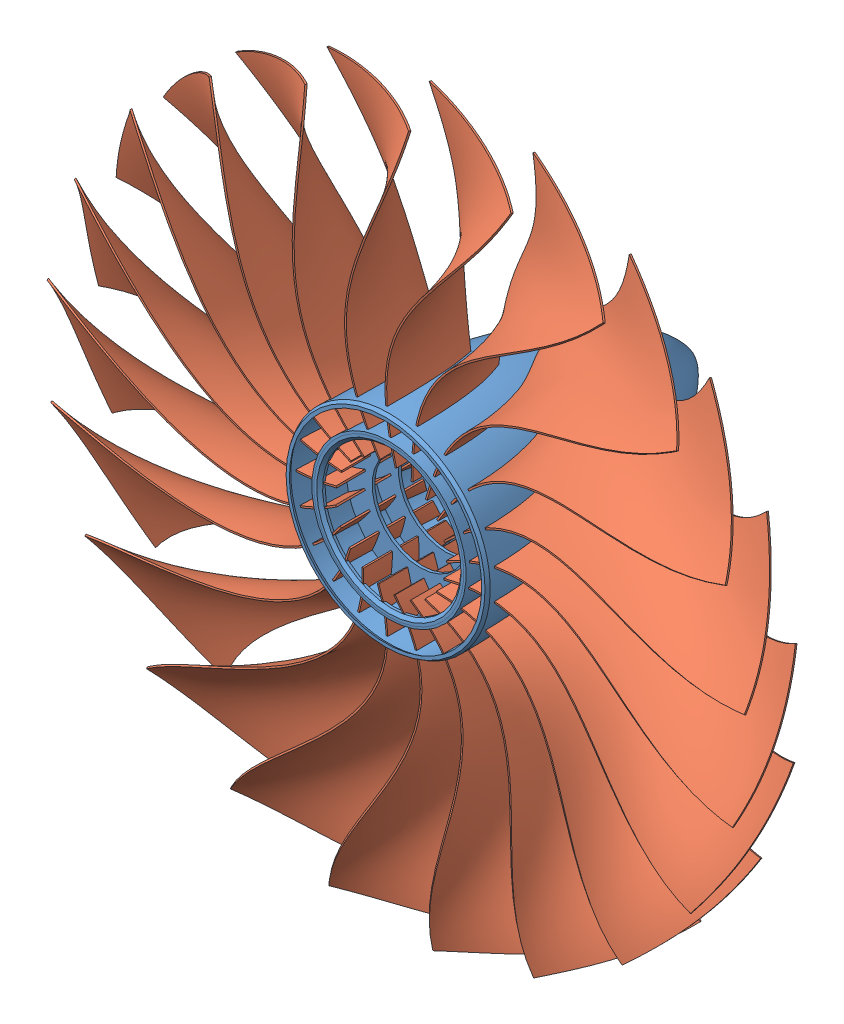
SolidWorks assembly fan turbine, configuration Défaut. Lengths in mm.
Overall size (6568.49 6570.8 2771.37).
2 component instances, 2 part files, 2 mates.
Components (placement in the parent):
- nez-2: nez [Défaut] at origin size (1902.11 1906.44 2770.01)
- fan jet engine-1: fan jet engine [Défaut] at origin size (6568.49 6570.8 1051.3)
Mates (geometry in assembly coordinates):
- Coïncidente1: coincident: axis of nez-2 through (0 0 32.2393) axis (0 0 -1); axis of fan jet engine-1 through (0 0 -573.1278) axis (0 0 1)
- Coïncidente2: coincident: plane of nez-2 through (0 0 0) normal (0 0 1); plane of fan jet engine-1 through (0 0 0) normal (0 0 1)
